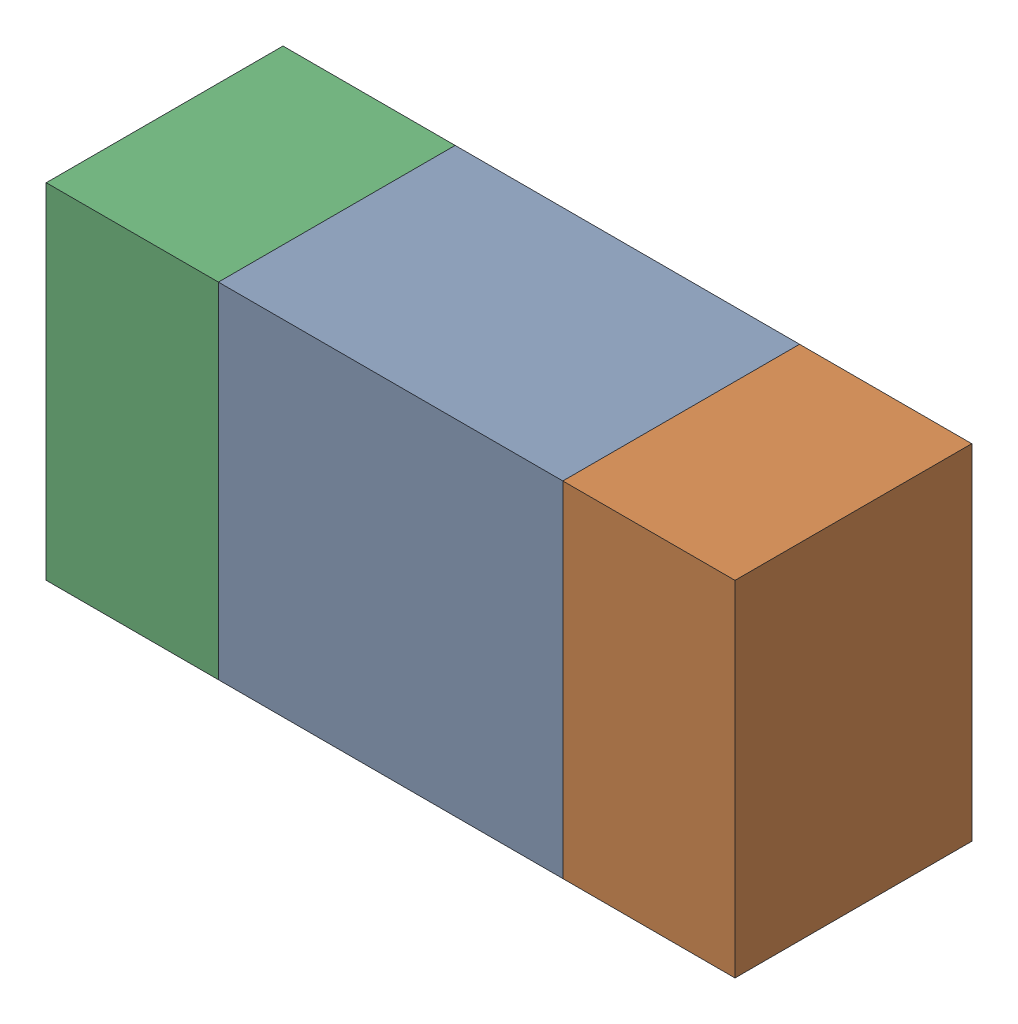
SolidWorks assembly R12, configuration ﾃﾞﾌｫﾙﾄ. Lengths in mm.
Overall size (1.6 0.8 0.55).
6 component instances, 2 part files, 0 mates.
Components (placement in the parent):
- 689261648-1: 689261648 [ﾃﾞﾌｫﾙﾄ] at (7 33.0001 0) size (0.8 0.8 0.55)
  - Extruded_33-1: Extruded_33 [ﾃﾞﾌｫﾙﾄ] at origin size (0.8 0.8 0.55)
- 689261512-1: 689261512 [ﾃﾞﾌｫﾙﾄ] at (7.6001 33.0001 0) size (0.4 0.8 0.55)
  - Extruded_32-1: Extruded_32 [ﾃﾞﾌｫﾙﾄ] at origin size (0.4 0.8 0.55)
- 689261512-2: 689261512 [ﾃﾞﾌｫﾙﾄ] at (6.4001 33.0001 0) size (0.4 0.8 0.55)
  - Extruded_32-1: Extruded_32 [ﾃﾞﾌｫﾙﾄ] at origin size (0.4 0.8 0.55)
